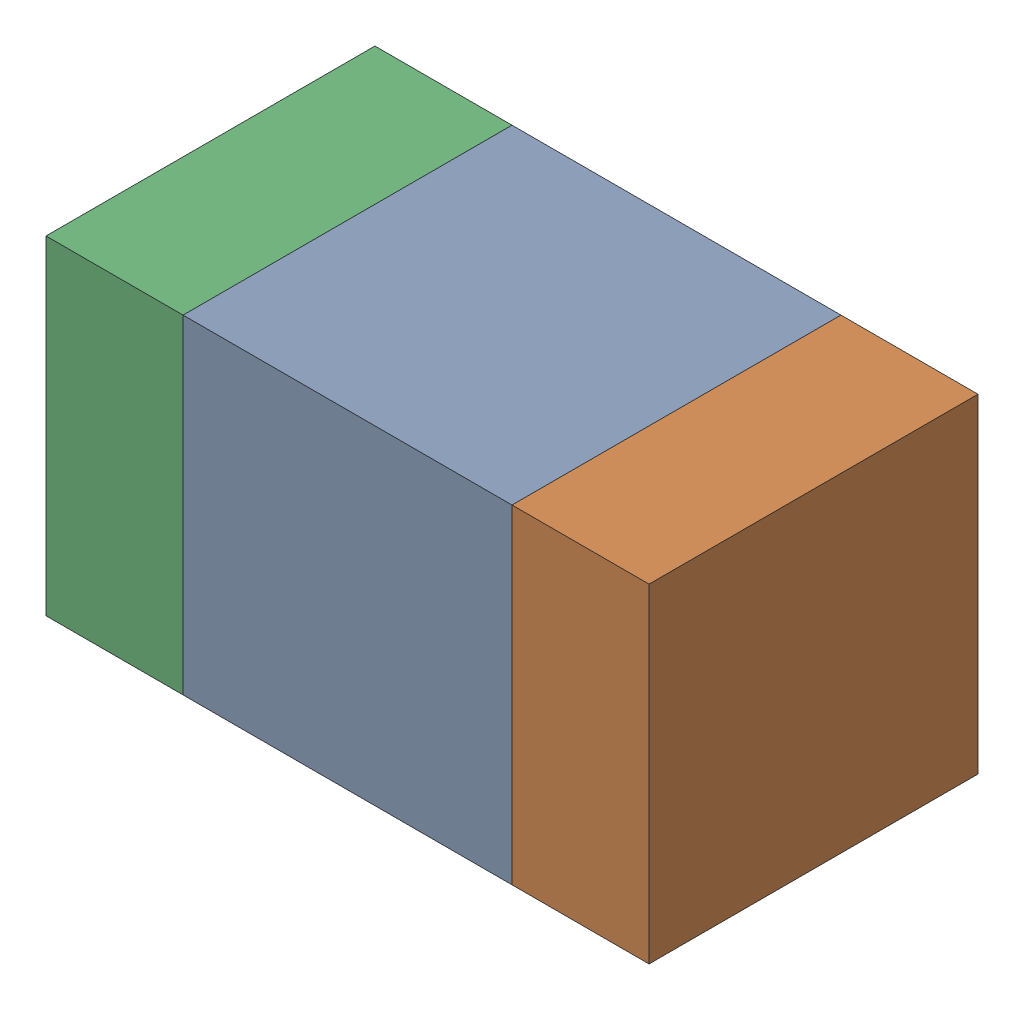
SolidWorks assembly C306_2PCB, configuration Default. Lengths in mm.
Overall size (1.1 0.6 0.6).
6 component instances, 2 part files, 0 mates.
Components (placement in the parent):
- 761606048-1: 761606048 [Default] at (130.8 93.8 0) size (0.6 0.6 0.6)
  - Extruded_9-1: Extruded_9 [Default] at origin size (0.6 0.6 0.6)
- 854785160-1: 854785160 [Default] at (131.225 93.8 0) size (0.25 0.6 0.6)
  - Extruded_19-1: Extruded_19 [Default] at origin size (0.25 0.6 0.6)
- 854785160-2: 854785160 [Default] at (130.375 93.8 0) size (0.25 0.6 0.6)
  - Extruded_19-1: Extruded_19 [Default] at origin size (0.25 0.6 0.6)
